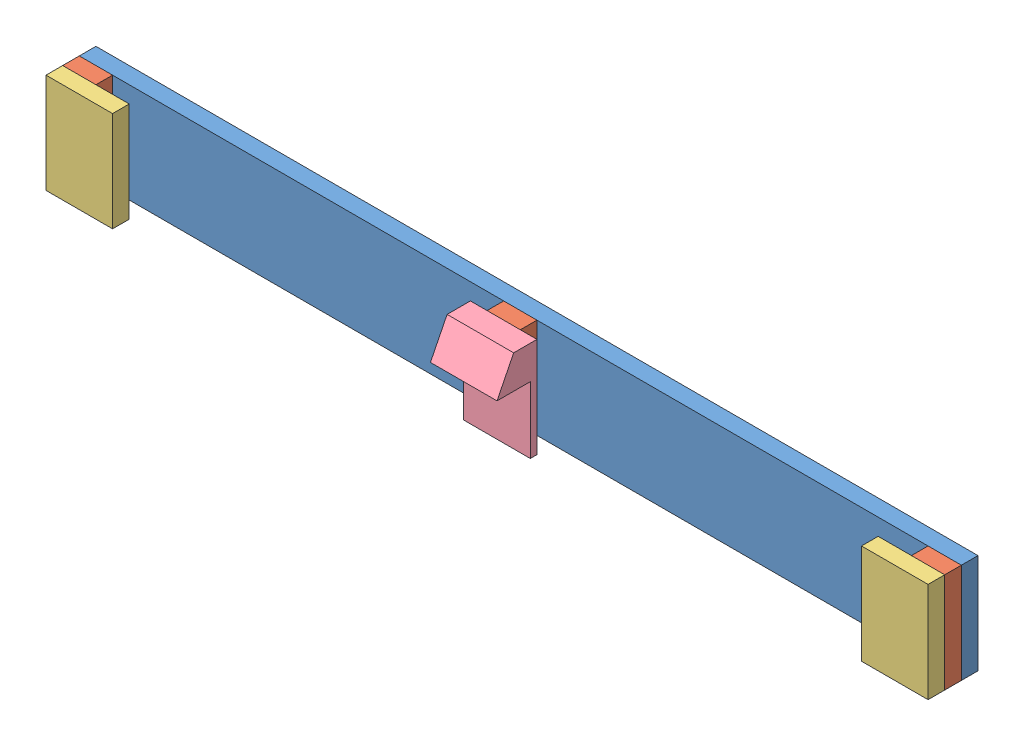
SolidWorks assembly slider, configuration Default. Lengths in mm.
Overall size (265 30 22).
7 component instances, 4 part files, 18 mates.
Components (placement in the parent):
- slider back-1: slider back [Default] at (-190.3065 9.9419 262.5) size (265 30 5)
- slider middle-1: slider middle [Default] at (-62.8065 9.9419 267.5) size (10 30 5)
- slider middle-2: slider middle [Default] at (-190.3065 9.9419 267.5) size (10 30 5)
- slider middle-3: slider middle [Default] at (64.6935 9.9419 267.5) size (10 30 5)
- slider top-1: slider top [Default] at (-190.3065 9.9419 272.5) size (20 30 5)
- slider top-3: slider top [Default] at (54.6935 9.9419 272.5) size (20 30 5)
- clip2-1: clip2 [Default] at (-67.8065 9.9419 272.5) size (20 30 12)
Mates (geometry in assembly coordinates):
- Coincident2: coincident aligned: plane of slider back-1 through (-190.3065 39.9419 267.5) normal (0 1 0); plane of slider middle-3 through (64.6935 39.9419 272.5) normal (0 1 0)
- Coincident3: coincident anti-aligned: plane of slider back-1 through (-190.3065 9.9419 267.5) normal (0 0 1); plane of slider middle-3 through (64.6935 9.9419 267.5) normal (0 0 -1)
- Coincident4: coincident aligned: plane of slider back-1 through (74.6935 9.9419 267.5) normal (1 0 0); plane of slider middle-3 through (74.6935 9.9419 272.5) normal (1 0 0)
- Coincident5: coincident aligned: plane of slider back-1 through (-190.3065 9.9419 267.5) normal (-1 0 0); plane of slider middle-2 through (-190.3065 9.9419 272.5) normal (-1 0 0)
- Coincident6: coincident anti-aligned: plane of slider back-1 through (-190.3065 9.9419 267.5) normal (0 0 1); plane of slider middle-2 through (-190.3065 9.9419 267.5) normal (0 0 -1)
- Coincident7: coincident aligned: plane of slider back-1 through (-190.3065 39.9419 267.5) normal (0 1 0); plane of slider middle-2 through (-190.3065 39.9419 272.5) normal (0 1 0)
- Coincident10: coincident aligned: plane of slider back-1 through (-190.3065 39.9419 267.5) normal (0 1 0); plane of slider middle-1 through (-62.8065 39.9419 272.5) normal (0 1 0)
- Coincident11: coincident anti-aligned: plane of slider back-1 through (-190.3065 9.9419 267.5) normal (0 0 1); plane of slider middle-1 through (-62.8065 9.9419 267.5) normal (0 0 -1)
- Coincident12: coincident: moEndPointRef_w of slider back-1; moEndPointRef_w of slider middle-1
- Coincident13: coincident aligned: plane of slider middle-2 through (-190.3065 9.9419 272.5) normal (-1 0 0); plane of slider top-1 through (-190.3065 9.9419 277.5) normal (-1 0 0)
- Coincident14: coincident anti-aligned: plane of slider middle-2 through (-190.3065 9.9419 272.5) normal (0 0 1); plane of slider top-1 through (-190.3065 9.9419 272.5) normal (0 0 -1)
- Coincident15: coincident aligned: plane of slider middle-2 through (-190.3065 39.9419 272.5) normal (0 1 0); plane of slider top-1 through (-190.3065 39.9419 277.5) normal (0 1 0)
- Coincident19: coincident anti-aligned: plane of slider middle-3 through (64.6935 9.9419 272.5) normal (0 0 1); plane of slider top-3 through (54.6935 9.9419 272.5) normal (0 0 -1)
- Coincident20: coincident aligned: plane of slider back-1 through (-190.3065 39.9419 267.5) normal (0 1 0); plane of slider top-3 through (54.6935 39.9419 277.5) normal (0 1 0)
- Coincident21: coincident aligned: plane of slider back-1 through (74.6935 9.9419 267.5) normal (1 0 0); plane of slider top-3 through (74.6935 9.9419 277.5) normal (1 0 0)
- Coincident31: coincident: moEndPointRef_w of slider middle-1; moEndPointRef_w of clip2-1
- Coincident32: coincident: plane of slider middle-1 through (-62.8065 9.9419 272.5) normal (0 0 1); plane of clip2-1 through (-67.8065 9.9419 272.5) normal (0 0 -1)
- Coincident33: coincident aligned: plane of slider middle-1 through (-62.8065 39.9419 272.5) normal (0 1 0); plane of clip2-1 through (-67.8065 39.9419 274.5) normal (0 1 0)
